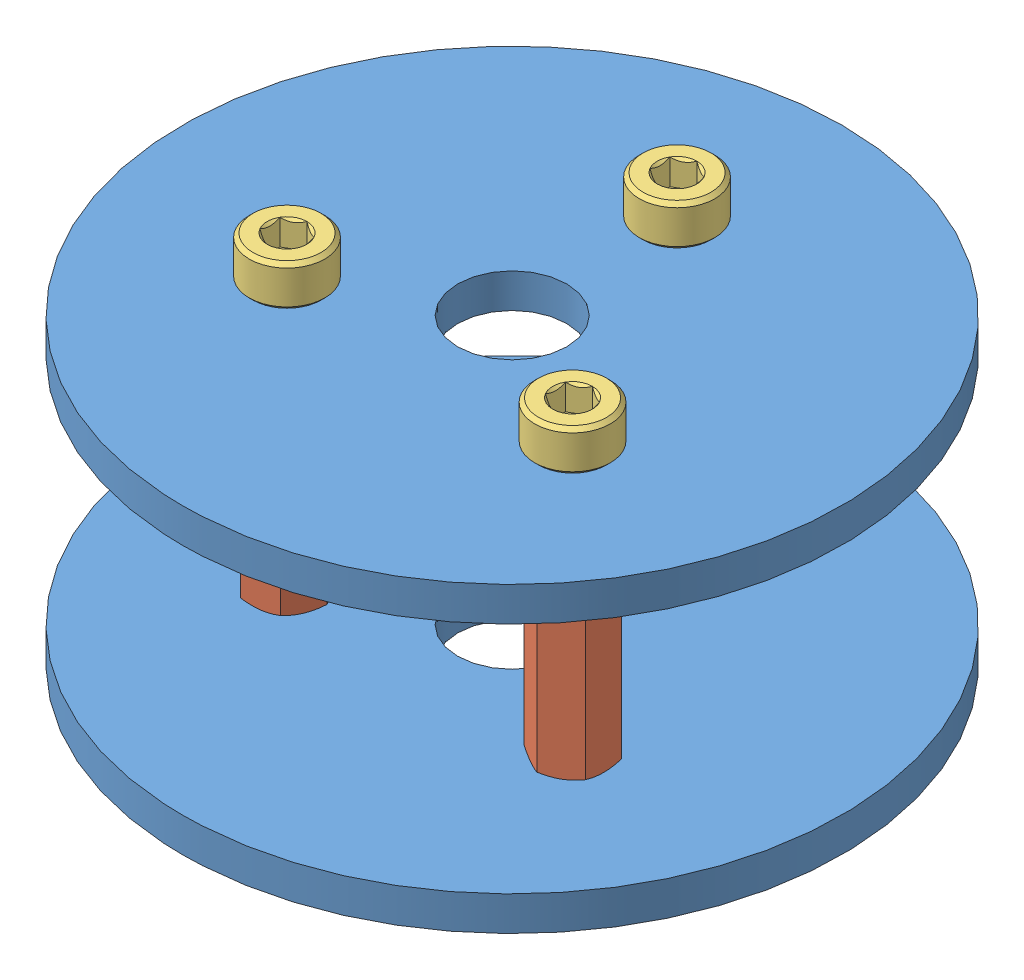
SolidWorks assembly BearingWheelAssem, configuration Default. Lengths in mm.
Overall size (47.99 28.29 47.99).
11 component instances, 3 part files, 26 mates.
Components (placement in the parent):
- bearingWheel2-1: bearingWheel2 [Default] at origin size (47.99 2.5 47.99)
- bearingWheel2-2: bearingWheel2 [Default] at (0 19.5 0) size (47.99 2.5 47.99)
- M3_17MM_Standoff-1: M3_17MM_Standoff [95947A512] at (10.3891 11 5.9982) x (1 0 0) z (0 -1 0) size (15.56 9.34 17.69)
- M3_8MM_SocketHead-1: M3_8MM_SocketHead [91292A112] at (-10.3891 14 5.9982) x (1 0 0) z (0 -1 0) size (5.5 5.5 11.58)
- M3_17MM_Standoff-2: M3_17MM_Standoff [95947A512] at (-10.3891 11 5.9982) x (-0.925434 0 -0.378909) z (0 -1 0) size (15.56 9.34 17.69)
- M3_8MM_SocketHead-2: M3_8MM_SocketHead [91292A112] at (0 14 -11.9963) x (1 0 0) z (0 -1 0) size (5.5 5.5 11.58)
- M3_17MM_Standoff-3: M3_17MM_Standoff [95947A512] at (0 11 -11.9963) x (1 0 0) z (0 -1 0) size (15.56 9.34 17.69)
- M3_8MM_SocketHead-3: M3_8MM_SocketHead [91292A112] at (10.3891 14 5.9982) x (1 0 0) z (0 -1 0) size (5.5 5.5 11.58)
- M3_8MM_SocketHead-4: M3_8MM_SocketHead [91292A112] at (-10.3891 8 5.9982) x (1 0 0) z (0 1 0) size (5.5 5.5 11.58)
- M3_8MM_SocketHead-5: M3_8MM_SocketHead [91292A112] at (0 8 -11.9963) x (-0.837169 0 -0.546944) z (0 1 0) size (5.5 5.5 11.58)
- M3_8MM_SocketHead-6: M3_8MM_SocketHead [91292A112] at (10.3891 8 5.9982) x (1 0 0) z (0 1 0) size (5.5 5.5 11.58)
Mates (geometry in assembly coordinates):
- Concentric1: concentric aligned: circle of bearingWheel2-1; circle of bearingWheel2-2
- Concentric2: concentric aligned: circle of bearingWheel2-1; circle of bearingWheel2-2
- Coincident3: coincident anti-aligned: plane of bearingWheel2-1 through (0 2.5 0) normal (0 1 0); plane of M3_17MM_Standoff-1 through (10.3891 2.5 8.5962) normal (0 -1 0)
- Coincident4: coincident anti-aligned: plane of bearingWheel2-1 through (0 2.5 0) normal (0 1 0); plane of M3_17MM_Standoff-3 through (0 2.5 -9.3983) normal (0 -1 0)
- Concentric4: concentric aligned: circle of bearingWheel2-1; circle of M3_17MM_Standoff-1
- Concentric5: concentric aligned: circle of bearingWheel2-1; circle of M3_17MM_Standoff-3
- Coincident5: coincident anti-aligned: plane of bearingWheel2-2 through (0 19.5 0) normal (0 -1 0); plane of M3_17MM_Standoff-1 through (10.3891 19.5 8.5962) normal (0 1 0)
- Coincident6: coincident anti-aligned: plane of bearingWheel2-1 through (0 0 0) normal (0 -1 0); plane of M3_8MM_SocketHead-5 through (0 0 -11.9963) normal (0 1 0)
- Coincident7: coincident anti-aligned: plane of bearingWheel2-1 through (0 0 0) normal (0 -1 0); plane of M3_8MM_SocketHead-6 through (10.3891 0 5.9982) normal (0 1 0)
- Coincident8: coincident anti-aligned: plane of bearingWheel2-1 through (0 0 0) normal (0 -1 0); plane of M3_8MM_SocketHead-4 through (-10.3891 0 5.9982) normal (0 1 0)
- Concentric6: concentric anti-aligned: circle of bearingWheel2-1; circle of M3_8MM_SocketHead-6
- Concentric7: concentric anti-aligned: circle of bearingWheel2-1; circle of M3_8MM_SocketHead-5
- Concentric8: concentric anti-aligned: circle of bearingWheel2-1; circle of M3_8MM_SocketHead-4
- Coincident9: coincident anti-aligned: plane of bearingWheel2-1 through (0 2.5 0) normal (0 1 0); plane of M3_17MM_Standoff-2 through (-9.4047 2.5 3.5938) normal (0 -1 0)
- Coincident10: coincident anti-aligned: plane of bearingWheel2-2 through (0 22 0) normal (0 1 0); plane of M3_8MM_SocketHead-2 through (0 22 -11.9963) normal (0 -1 0)
- Coincident11: coincident anti-aligned: plane of bearingWheel2-2 through (0 22 0) normal (0 1 0); plane of M3_8MM_SocketHead-3 through (10.3891 22 5.9982) normal (0 -1 0)
- Coincident12: coincident anti-aligned: plane of bearingWheel2-2 through (0 22 0) normal (0 1 0); plane of M3_8MM_SocketHead-1 through (-10.3891 22 5.9982) normal (0 -1 0)
- Concentric9: concentric aligned: circle of bearingWheel2-2; circle of M3_8MM_SocketHead-2
- Concentric10: concentric aligned: circle of bearingWheel2-2; circle of M3_8MM_SocketHead-3
- Concentric12: concentric aligned: circle of bearingWheel2-2; circle of M3_8MM_SocketHead-1
- Lock1: lock: unknown of M3_8MM_SocketHead-1; unknown of M3_8MM_SocketHead-2
- Lock2: lock: unknown of M3_8MM_SocketHead-2; unknown of M3_8MM_SocketHead-3
- Lock3: lock: unknown of M3_17MM_Standoff-2; unknown of M3_17MM_Standoff-3
- Lock4: lock: unknown of M3_17MM_Standoff-1; unknown of M3_17MM_Standoff-3
- Lock5: lock: unknown of M3_8MM_SocketHead-5; unknown of M3_8MM_SocketHead-6
- Lock6: lock: unknown of M3_8MM_SocketHead-4; unknown of M3_8MM_SocketHead-5
